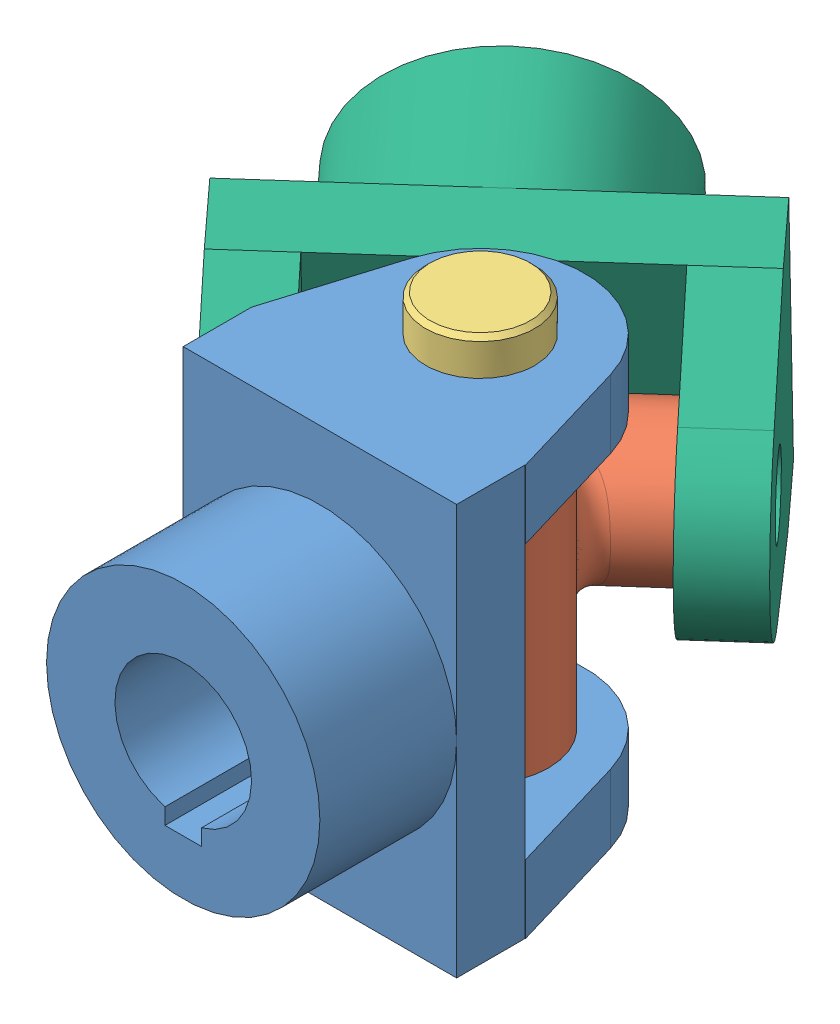
SolidWorks assembly Assem1, configuration Default. Lengths in mm.
Overall size (132759.38 113000 164240.39).
6 component instances, 6 part files, 7 mates.
Components (placement in the parent):
- Part2-1: Part2 [Default] at (-9353.3663 29170.5109 102813.0417) size (60088.42 90000 88000)
- Part3-1: Part3 [Default] at (-9181.0561 59170.5109 82813.0417) x (-0.664756 0 -0.747061) z (0.747061 0 -0.664756) size (53000 60000 60000)
- Part4-1: Part4 [Default] at (-9181.0561 82170.5109 82813.0417) x (0.995408 0 0.095721) z (0 -1 0) size (24000 24000 113000)
- Part5-1: Part5 [Default] at (-9181.0561 -20049.7138 82813.0417) x (0.999999 0 -0.001181) z (0.001181 0 0.999999) size (24000 8000 24000)
- Part6-1: Part6 [Default] at (-7769.4946 -19829.4891 68134.1665) x (0.884278 0.459154 0.085035) z (-0.095721 0 0.995408) size (4000 4000 30000)
- Part7-1: Part7 [Default] at (-37451.3318 33496.4831 51042.5647) x (-0.138184 -0.978156 -0.155292) z (-0.650235 0.207871 -0.730742) size (60088.42 90000 88000)
Mates (geometry in assembly coordinates):
- Coincident2: coincident aligned: circle of Part2-1; circle of Part3-1
- Coincident3: coincident anti-aligned: plane of Part2-1 through (-39353.3663 74170.5109 117813.0417) normal (0 1 0); circle of Part4-1
- Concentric1: concentric aligned: cylinder of Part2-1 through (-9181.0561 59170.5109 82813.0417) axis (0 1 0) radius 8000; cylinder of Part4-1 through (-9181.0561 -30829.4891 82813.0417) axis (0 1 0) radius 8000
- Concentric2: concentric anti-aligned: cylinder of Part4-1 through (-9181.0561 -30829.4891 82813.0417) axis (0 1 0) radius 8000; cylinder of Part5-1 through (-9181.0561 -16049.7138 82813.0417) axis (0 -1 0) radius 8000
- Concentric3: concentric anti-aligned: cylinder of Part4-1 through (-8032.4014 -19829.4891 70868.1436) axis (-0.095721 0 0.995408) radius 2000; cylinder of Part6-1 through (-10641.1312 -19829.4891 97996.412) axis (0.095721 0 -0.995408) radius 2000
- Coincident8: coincident anti-aligned: plane of Part3-1 through (-46882.261 29170.5109 85573.3224) normal (-0.747061 0 0.664756); plane of Part7-1 through (-46882.261 29170.5109 85573.3224) normal (0.747061 0 -0.664756)
- Coincident9: coincident aligned: cylinder of Part3-1 through (-2058.621 29170.5109 45687.9704) axis (-0.747061 0 0.664756) radius 8000; circle of Part7-1
